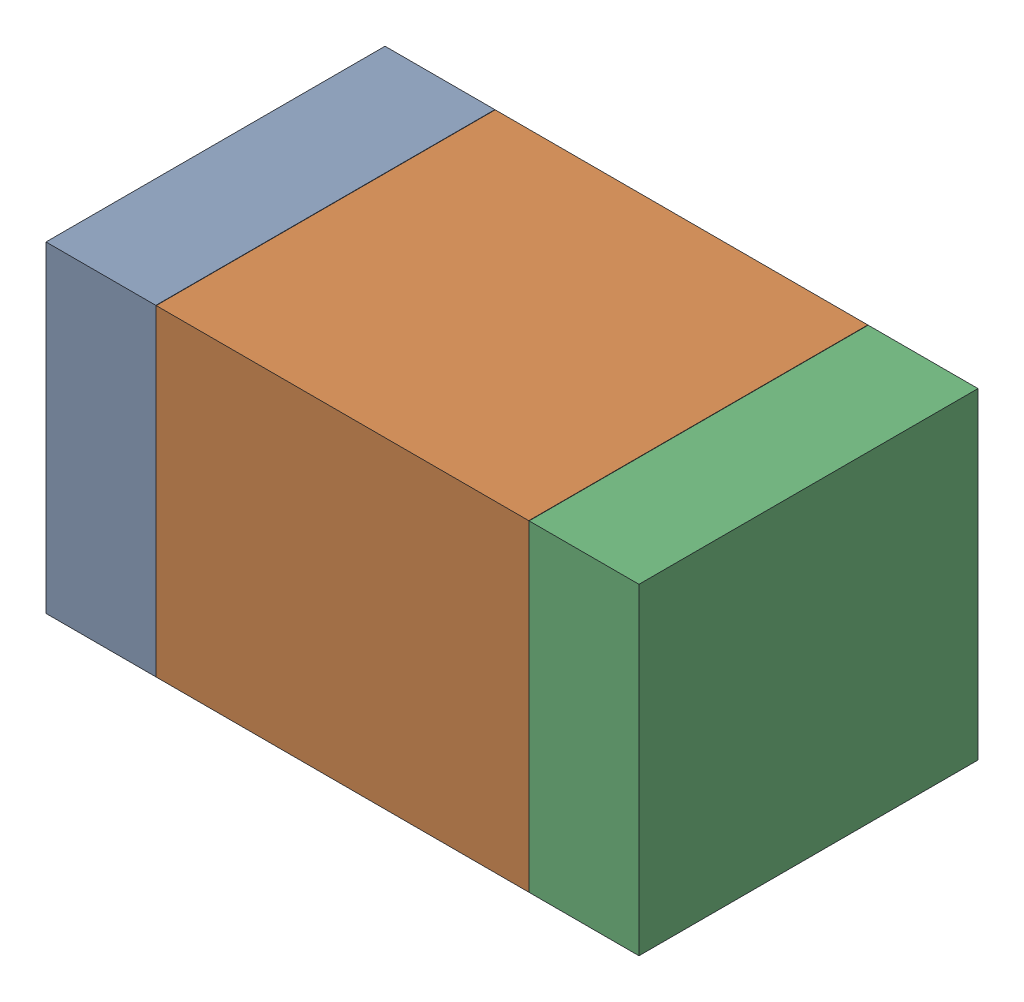
SolidWorks assembly R42, configuration Default. Lengths in mm.
Overall size (1.75 0.95 1).
6 component instances, 2 part files, 0 mates.
Components (placement in the parent):
- 6575498272-1: 6575498272 [Default] at (44.4995 10.795 0) size (0.32 0.95 1)
  - Extruded_8-1: Extruded_8 [Default] at origin size (0.32 0.95 1)
- 6575498112-1: 6575498112 [Default] at (45.212 10.795 0) size (1.1 0.95 1)
  - Extruded_9-1: Extruded_9 [Default] at origin size (1.1 0.95 1)
- 6575498272-2: 6575498272 [Default] at (45.9245 10.795 0) size (0.32 0.95 1)
  - Extruded_8-1: Extruded_8 [Default] at origin size (0.32 0.95 1)
